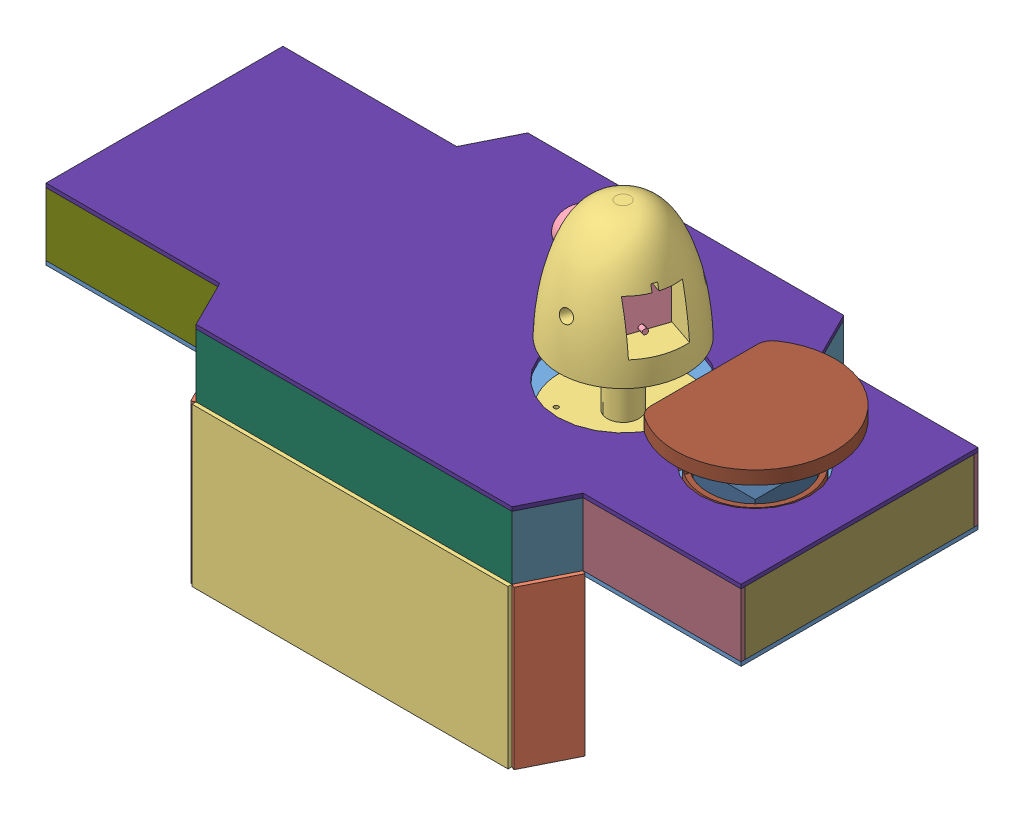
SolidWorks assembly ShellAssem, configuration Default. Lengths in mm.
Overall size (558.8 306.04 273.05).
46 component instances, 26 part files, 68 mates.
Components (placement in the parent):
- BasePlate-1: BasePlate [Default] at (-0.2928 -5.4567 3.8617) size (558.8 3.17 266.7)
- LowerPanelThin-1: LowerPanelThin [Default] at (-130.4678 -67.3692 118.1617) x (0.447214 0 0.894427) z (-0.894427 0 0.447214) size (42.6 127 3.17)
- LowerPanelThin-2: LowerPanelThin [Default] at (145.422 -67.3692 119.5816) x (-0.447214 0 0.894427) z (-0.894427 0 -0.447214) size (42.6 127 3.17)
- LowerPanelThin-3: LowerPanelThin [Default] at (-133.3076 -67.3692 -111.8582) x (-0.447214 0 0.894427) z (0.894427 0 0.447214) size (42.6 127 3.17)
- LowerPanelThin-4: LowerPanelThin [Default] at (142.5822 -67.3692 -110.4383) x (-0.447214 0 -0.894427) z (0.894427 0 -0.447214) size (42.6 127 3.17)
- LowerPanelWide-1: LowerPanelWide [Default] at (6.0572 -67.3692 -131.0758) size (254 127 3.17)
- LowerPanelWide-2: LowerPanelWide [Default] at (6.0572 -67.3692 138.7992) size (254 127 3.17)
- BatteryCaseLAssem-1: BatteryCaseLAssem [Default] at (-70.9297 -9.0701 32.2651) x (-1 0 0) z (0 0 -1) size (142.88 26.04 63.5)
  - BatteryCaseShort-1: BatteryCaseShort [Default] at (-92.8619 -9.4041 55.3909) size (114.3 22.86 3.17)
  - BatteryCaseLong-1: BatteryCaseLong [Default] at (-80.1619 -9.4041 115.7159) size (139.7 22.86 3.17)
  - BatteryCaseEnd-1: BatteryCaseEnd [Default] at (-8.7244 -9.4041 95.0784) x (0 0 1) z (0 -1 0) size (44.45 3.17 22.86)
  - Part7^BatteryCaseLAssem-1: Part7^BatteryCaseLAssem [Default] at origin (virtual)
  - Part8^BatteryCaseLAssem-1: Part8^BatteryCaseLAssem [Default] at origin (virtual)
  - Part9-1: Part9 [Default] at (0 -22.4216 0) x (1 0 0) z (0 1 0) size (142.88 63.5 3.17)
- BatteryCaseRAssem-1: BatteryCaseRAssem [Default] at (-70.9297 -27.8782 -24.5418) x (-1 0 0) z (0 0 1) size (142.88 26.04 63.5)
  - BatteryCaseShort-1: BatteryCaseShort [Default] at (-92.8619 -9.4041 55.3909) size (114.3 22.86 3.17)
  - BatteryCaseLong-1: BatteryCaseLong [Default] at (-80.1619 -9.4041 115.7159) size (139.7 22.86 3.17)
  - BatteryCaseEnd-1: BatteryCaseEnd [Default] at (-8.7244 -9.4041 95.0784) x (0 0 1) z (0 -1 0) size (44.45 3.17 22.86)
  - Part7^BatteryCaseRAssem-1: Part7^BatteryCaseRAssem [Default] at origin (virtual)
  - Part8^BatteryCaseRAssem-1: Part8^BatteryCaseRAssem [Default] at origin (virtual)
  - Part9-1: Part9 [Default] at (0 3.6134 0) x (1 0 0) z (0 1 0) size (142.88 63.5 3.17)
- NUC-1: NUC [Default] at (-220.6234 -3.8692 -63.9843) size (111 48.26 114.81)
- LIDAR_case-1: LIDAR_case [Default] at (245.1871 5.6558 53.8053) x (0 0 -1) z (1 0 0) size (128.27 85.36 108.59)
  - LIDAR_base-1: LIDAR_base [Default] at origin size (88.9 11.68 88.9)
  - LIDAR-1: LIDAR [Default] at (19.45 3.0942 -69.45) size (50 70.6 50)
  - LIDAR_top-1: LIDAR_top [Default] at (44.45 2.794 -44.45) x (0 0 -1) z (1 0 0) size (105.42 82.56 128.27)
- UpperFront-1: UpperFront [Default] at (-278.1053 21.5308 3.8617) x (0 0 1) z (-1 0 0) size (184.15 50.8 3.17)
- UpperFront-2: UpperFront [Default] at (277.5197 21.5308 3.8617) x (0 0 1) z (-1 0 0) size (184.15 50.8 3.17)
- UpperFrontWall-1: UpperFrontWall [Default] at (215.6072 21.5308 -89.8008) size (127 50.8 3.17)
- UpperFrontWall-2: UpperFrontWall [Default] at (215.6072 21.5308 97.5242) size (127 50.8 3.17)
- UpperAngleWallSmall-1: UpperAngleWallSmall [Default] at (141.1791 21.5308 117.4182) x (0.447214 0 -0.894427) z (0.894427 0 0.447214) size (42.67 50.8 3.17)
- UpperAngleWallSmall-3: UpperAngleWallSmall [Default] at (141.1791 21.5308 -109.6949) x (0.447214 0 0.894427) z (-0.894427 0 0.447214) size (42.67 50.8 3.17)
- UpperAngleWallSmall-4: UpperAngleWallSmall [Default] at (-129.0646 21.5308 -109.6949) x (0.447214 0 -0.894427) z (0.894427 0 0.447214) size (42.67 50.8 3.17)
- UpperAngleWallSmall-5: UpperAngleWallSmall [Default] at (-129.0646 21.5308 117.4182) x (-0.447214 0 -0.894427) z (0.894427 0 -0.447214) size (42.67 50.8 3.17)
- UpperAngleWallLarge-1: UpperAngleWallLarge [Default] at (6.0572 21.5308 -127.9008) size (254 50.8 3.17)
- UpperAngleWallLarge-2: UpperAngleWallLarge [Default] at (6.0572 21.5308 135.6242) size (254 50.8 3.17)
- UpperRearWall-1: UpperRearWall [Default] at (-209.8428 21.5308 97.5242) size (139.7 50.8 3.17)
- UpperRearWall-2: UpperRearWall [Default] at (-209.8428 21.5308 -89.8008) size (139.7 50.8 3.17)
- CoverPlate-1: CoverPlate [Default] at (-0.2928 48.5183 3.8617) size (558.8 3.17 266.7)
- LidarLift-1: LidarLift [Default] at (200.7371 0.8933 9.3553) size (88.9 9.53 88.9)
- pan_mechanism-2: pan_mechanism [Default] at (89.0568 -3.8692 3.8617) x (-0.411635 0 0.911349) z (-0.911349 0 -0.411635) size (126.7 179.04 129.89)
  - bottom_pan - Copy-1: bottom_pan - Copy [Default] at origin size (107.09 5.96 107.09)
  - top_pan-1: top_pan [Default] at (0 20.6883 0) x (0.97893 0 -0.204197) z (0.204197 0 0.97893) size (107.09 5.96 107.09)
  - Assem1-2: Assem1 [Default] at (0.0312 26.6446 -0.0302) x (0.99519 0 -0.097967) z (0.097967 0 0.99519) size (102.46 152.4 113.08)
    - among_us-1: among_us [Default] x (0 0 -1) z (1 0 0) size (103.27 152.4 102.46)
    - camera-1: camera [Default] at (0 95.3 -23.4507) size (38.5 38.2 90.38)
Mates (geometry in assembly coordinates):
- Coincident1: coincident anti-aligned: plane of BasePlate-1 through (-139.9928 -3.8692 99.1117) normal (-0.894427 0 0.447214); plane of LowerPanelThin-1 through (-130.4678 -67.3692 118.1617) normal (0.894427 0 -0.447214)
- Coincident2: coincident aligned: line of BasePlate-1 through (-139.9928 -3.8692 99.1117) axis (0 -1 0); line of LowerPanelThin-1 through (-139.9928 -3.8692 99.1117) axis (0 -1 0)
- Coincident3: coincident aligned: plane of BasePlate-1 through (-0.2928 -3.8692 3.8617) normal (0 1 0); plane of LowerPanelThin-1 through (-142.8326 -3.8692 100.5316) normal (0 1 0)
- Coincident4: coincident anti-aligned: plane of BasePlate-1 through (133.0572 -3.8692 137.2117) normal (0.894427 0 0.447214); plane of LowerPanelThin-2 through (142.5822 -67.3692 118.1617) normal (-0.894427 0 -0.447214)
- Coincident5: coincident aligned: plane of BasePlate-1 through (-0.2928 -3.8692 3.8617) normal (0 1 0); plane of LowerPanelThin-2 through (152.1072 -3.8692 99.1117) normal (0 1 0)
- Coincident6: coincident aligned: line of BasePlate-1 through (152.1072 -3.8692 99.1117) axis (0 -1 0); line of LowerPanelThin-2 through (152.1072 -3.8692 99.1117) axis (0 -1 0)
- Coincident7: coincident anti-aligned: plane of BasePlate-1 through (-139.9928 -3.8692 -91.3883) normal (-0.894427 0 -0.447214); plane of LowerPanelThin-3 through (-130.4678 -67.3692 -110.4383) normal (0.894427 0 0.447214)
- Coincident8: coincident aligned: plane of BasePlate-1 through (-0.2928 -3.8692 3.8617) normal (0 1 0); plane of LowerPanelThin-3 through (-120.9428 -3.8692 -129.4883) normal (0 1 0)
- Coincident9: coincident aligned: line of BasePlate-1 through (-139.9928 -3.8692 -91.3883) axis (0 -1 0); line of LowerPanelThin-3 through (-139.9928 -3.8692 -91.3883) axis (0 -1 0)
- Coincident10: coincident anti-aligned: plane of BasePlate-1 through (133.0572 -3.8692 -129.4883) normal (0.894427 0 -0.447214); plane of LowerPanelThin-4 through (142.5822 -67.3692 -110.4383) normal (-0.894427 0 0.447214)
- Coincident11: coincident aligned: plane of BasePlate-1 through (-0.2928 -3.8692 3.8617) normal (0 1 0); plane of LowerPanelThin-4 through (154.947 -3.8692 -92.8082) normal (0 1 0)
- Coincident12: coincident aligned: line of BasePlate-1 through (152.1072 -3.8692 -91.3883) axis (0 -1 0); line of LowerPanelThin-4 through (152.1072 -3.8692 -91.3883) axis (0 -1 0)
- Coincident13: coincident anti-aligned: plane of BasePlate-1 through (-120.9428 -3.8692 -129.4883) normal (0 0 -1); plane of LowerPanelWide-1 through (6.0572 -67.3692 -129.4883) normal (0 0 1)
- Coincident14: coincident aligned: plane of BasePlate-1 through (-0.2928 -3.8692 3.8617) normal (0 1 0); plane of LowerPanelWide-1 through (-120.9428 -3.8692 -129.4883) normal (0 1 0)
- Coincident16: coincident anti-aligned: line of LowerPanelThin-3 through (-120.9428 -130.8692 -129.4883) axis (0 1 0); line of LowerPanelWide-1 through (-120.9428 -3.8692 -129.4883) axis (0 -1 0)
- Coincident17: coincident anti-aligned: plane of BasePlate-1 through (-120.9428 -3.8692 137.2117) normal (0 0 1); plane of LowerPanelWide-2 through (6.0572 -67.3692 137.2117) normal (0 0 -1)
- Coincident18: coincident aligned: plane of BasePlate-1 through (-0.2928 -3.8692 3.8617) normal (0 1 0); plane of LowerPanelWide-2 through (-120.9428 -3.8692 140.3867) normal (0 1 0)
- Coincident19: coincident anti-aligned: line of LowerPanelThin-1 through (-120.9428 -130.8692 137.2117) axis (0 1 0); line of LowerPanelWide-2 through (-120.9428 -3.8692 137.2117) axis (0 -1 0)
- Coincident21: coincident aligned: line of BasePlate-1 through (-63.7928 -7.0442 -85.0383) axis (1 0 0); line of BatteryCaseLAssem-1/BatteryCaseLong-1 through (-60.6178 -7.0442 -85.0383) axis (1 0 0)
- Coincident22: coincident anti-aligned: line of BasePlate-1 through (-63.7928 -7.0442 -21.5383) axis (0 0 -1); line of BatteryCaseLAssem-1/BatteryCaseEnd-1 through (-63.7928 -7.0442 -85.0383) axis (0 0 1)
- Coincident23: coincident anti-aligned: line of BasePlate-1 through (-63.7928 -7.0442 92.7617) axis (1 0 0); line of BatteryCaseRAssem-1/BatteryCaseLong-1 through (79.0822 -7.0442 92.7617) axis (-1 0 0)
- Coincident24: coincident aligned: line of BasePlate-1 through (-63.7928 -7.0442 29.2617) axis (0 0 1); line of BatteryCaseRAssem-1/BatteryCaseEnd-1 through (-63.7928 -7.0442 48.3117) axis (0 0 1)
- Coincident25: coincident anti-aligned: plane of BasePlate-1 through (-0.2928 -3.8692 3.8617) normal (0 1 0); plane of NUC-1 through (-220.6234 -3.8692 50.8237) normal (0 -1 0)
- Coincident31: coincident anti-aligned: line of BasePlate-1 through (-276.5178 -3.8692 95.9367) axis (0 0 -1); line of UpperFront-1 through (-276.5178 -3.8692 -88.2133) axis (0 0 1)
- Coincident32: coincident anti-aligned: line of BasePlate-1 through (-279.6928 -3.8692 99.1117) axis (0 0 -1); line of UpperFront-1 through (-279.6928 -3.8692 -88.2133) axis (0 0 1)
- Coincident33: coincident: point of assembly; point of BasePlate-1; point of UpperFront-1
- Coincident34: coincident aligned: line of BasePlate-1 through (275.9322 -3.8692 -88.2133) axis (0 0 1); line of UpperFront-2 through (275.9322 -3.8692 -88.2133) axis (0 0 1)
- Coincident35: coincident aligned: line of BasePlate-1 through (279.1072 -3.8692 -91.3883) axis (0 0 1); line of UpperFront-2 through (279.1072 -3.8692 -88.2133) axis (0 0 1)
- Coincident36: coincident: point of assembly; point of BasePlate-1; point of UpperFront-2
- Coincident37: coincident anti-aligned: plane of UpperFront-2 through (275.9322 -3.8692 -88.2133) normal (0 0 -1); plane of UpperFrontWall-1 through (215.6072 21.5308 -88.2133) normal (0 0 1)
- Coincident38: coincident anti-aligned: plane of BasePlate-1 through (-0.2928 -3.8692 3.8617) normal (0 1 0); plane of UpperFrontWall-1 through (152.1072 -3.8692 -88.2133) normal (0 -1 0)
- Coincident39: coincident aligned: plane of BasePlate-1 through (279.1072 -3.8692 -91.3883) normal (1 0 0); plane of UpperFrontWall-1 through (279.1072 -3.8692 -88.2133) normal (1 0 0)
- Coincident40: coincident anti-aligned: plane of BasePlate-1 through (-0.2928 -3.8692 3.8617) normal (0 1 0); plane of UpperFrontWall-2 through (152.1072 -3.8692 99.1117) normal (0 -1 0)
- Coincident41: coincident aligned: plane of BasePlate-1 through (279.1072 -3.8692 -91.3883) normal (1 0 0); plane of UpperFrontWall-2 through (279.1072 -3.8692 99.1117) normal (1 0 0)
- Coincident42: coincident aligned: plane of BasePlate-1 through (152.1072 -3.8692 99.1117) normal (0 0 1); plane of UpperFrontWall-2 through (215.6072 21.5308 99.1117) normal (0 0 1)
- Coincident43: coincident anti-aligned: plane of BasePlate-1 through (-0.2928 -3.8692 3.8617) normal (0 1 0); plane of UpperAngleWallSmall-1 through (133.0572 -3.8692 137.2117) normal (0 -1 0)
- Coincident44: coincident anti-aligned: line of BasePlate-1 through (152.1072 -3.8692 99.1117) axis (-0.447214 0 0.894427); line of UpperAngleWallSmall-1 through (133.0572 -3.8692 137.2117) axis (0.447214 0 -0.894427)
- Coincident45: coincident: point of assembly; point of BasePlate-1; point of UpperAngleWallSmall-1
- Coincident47: coincident anti-aligned: plane of BasePlate-1 through (-0.2928 -3.8692 3.8617) normal (0 1 0); plane of UpperAngleWallSmall-5 through (-118.103 -3.8692 135.7918) normal (0 -1 0)
- Coincident48: coincident aligned: line of BasePlate-1 through (-120.9428 -3.8692 137.2117) axis (-0.447214 0 -0.894427); line of UpperAngleWallSmall-5 through (-120.9428 -3.8692 137.2117) axis (-0.447214 0 -0.894427)
- Coincident49: coincident: point of assembly; point of BasePlate-1; point of UpperAngleWallSmall-5
- Coincident50: coincident anti-aligned: plane of BasePlate-1 through (-0.2928 -3.8692 3.8617) normal (0 1 0); plane of UpperAngleWallSmall-4 through (-137.1865 -3.8692 -89.9014) normal (0 -1 0)
- Coincident51: coincident aligned: line of BasePlate-1 through (-139.9928 -3.8692 -91.3883) axis (0.447214 0 -0.894427); line of UpperAngleWallSmall-4 through (-140.0263 -3.8692 -91.3213) axis (0.447214 0 -0.894427)
- Coincident52: coincident: point of BasePlate-1; point of UpperAngleWallSmall-4
- Coincident53: coincident anti-aligned: plane of BasePlate-1 through (-0.2928 -3.8692 3.8617) normal (0 1 0); plane of UpperAngleWallSmall-3 through (130.2174 -3.8692 -128.0684) normal (0 -1 0)
- Coincident54: coincident aligned: line of BasePlate-1 through (133.0572 -3.8692 -129.4883) axis (0.447214 0 0.894427); line of UpperAngleWallSmall-3 through (133.0572 -3.8692 -129.4883) axis (0.447214 0 0.894427)
- Coincident56: coincident: point of assembly; point of BasePlate-1; point of UpperAngleWallSmall-3
- Coincident57: coincident anti-aligned: plane of BasePlate-1 through (-0.2928 -3.8692 3.8617) normal (0 1 0); plane of UpperAngleWallLarge-1 through (-120.9428 -3.8692 -126.3133) normal (0 -1 0)
- Coincident58: coincident aligned: line of BasePlate-1 through (-120.9428 -3.8692 -129.4883) axis (1 0 0); line of UpperAngleWallLarge-1 through (-120.9428 -3.8692 -129.4883) axis (1 0 0)
- Coincident59: coincident anti-aligned: line of UpperAngleWallSmall-4 through (-120.9428 -3.8692 -129.4883) axis (0 1 0); line of UpperAngleWallLarge-1 through (-120.9428 46.9308 -129.4883) axis (0 -1 0)
- Coincident60: coincident anti-aligned: plane of BasePlate-1 through (-0.2928 -3.8692 3.8617) normal (0 1 0); plane of UpperAngleWallLarge-2 through (-120.9428 -3.8692 137.2117) normal (0 -1 0)
- Coincident61: coincident anti-aligned: line of BasePlate-1 through (133.0572 -3.8692 137.2117) axis (-1 0 0); line of UpperAngleWallLarge-2 through (-120.9428 -3.8692 137.2117) axis (1 0 0)
- Coincident62: coincident anti-aligned: line of UpperAngleWallSmall-1 through (133.0572 46.9308 137.2117) axis (0 -1 0); line of UpperAngleWallLarge-2 through (133.0572 -3.8692 137.2117) axis (0 1 0)
- Coincident63: coincident anti-aligned: plane of BasePlate-1 through (-0.2928 -3.8692 3.8617) normal (0 1 0); plane of UpperRearWall-1 through (-279.6928 -3.8692 99.1117) normal (0 -1 0)
- Coincident64: coincident anti-aligned: line of BasePlate-1 through (-139.9928 -3.8692 99.1117) axis (-1 0 0); line of UpperRearWall-1 through (-279.6928 -3.8692 99.1117) axis (1 0 0)
- Coincident65: coincident aligned: plane of UpperFront-1 through (-279.6928 21.5308 3.8617) normal (-1 0 0); plane of UpperRearWall-1 through (-279.6928 -3.8692 99.1117) normal (-1 0 0)
- Coincident66: coincident aligned: plane of UpperFront-1 through (-279.6928 21.5308 3.8617) normal (-1 0 0); plane of UpperRearWall-2 through (-279.6928 -3.8692 -88.2133) normal (-1 0 0)
- Coincident67: coincident anti-aligned: plane of BasePlate-1 through (-0.2928 -3.8692 3.8617) normal (0 1 0); plane of UpperRearWall-2 through (-279.6928 -3.8692 -88.2133) normal (0 -1 0)
- Coincident68: coincident aligned: plane of BasePlate-1 through (-279.6928 -3.8692 -91.3883) normal (0 0 -1); plane of UpperRearWall-2 through (-209.8428 21.5308 -91.3883) normal (0 0 -1)
- Coincident69: coincident anti-aligned: plane of UpperFrontWall-1 through (152.1072 46.9308 -88.2133) normal (0 1 0); plane of CoverPlate-1 through (-0.2928 46.9308 3.8617) normal (0 -1 0)
- Coincident70: coincident aligned: plane of UpperAngleWallSmall-3 through (142.599 21.5308 -110.4048) normal (0.894427 0 -0.447214); plane of CoverPlate-1 through (133.0572 50.1058 -129.4883) normal (0.894427 0 -0.447214)
- Coincident71: coincident aligned: plane of UpperAngleWallSmall-1 through (142.599 21.5308 118.1282) normal (0.894427 0 0.447214); plane of CoverPlate-1 through (133.0572 50.1058 137.2117) normal (0.894427 0 0.447214)
- Coincident74: coincident aligned: circle of LIDAR_case-1/LIDAR_base-1; circle of LidarLift-1
- Coincident76: coincident anti-aligned: plane of BasePlate-1 through (-0.2928 -3.8692 3.8617) normal (0 1 0); plane of pan_mechanism-2/bottom_pan - Copy-1 through (89.0568 -3.8692 3.8617) normal (0 -1 0)
- Concentric1: concentric anti-aligned: cylinder of BasePlate-1 through (136.622 -24.1892 3.2661) axis (0 1 0) radius 1.4986; cylinder of pan_mechanism-2/bottom_pan - Copy-1 through (136.622 2.0871 3.2661) axis (0 -1 0) radius 1.4986
- Concentric2: concentric anti-aligned: circle of BasePlate-1; cylinder of pan_mechanism-2/bottom_pan - Copy-1 through (41.4917 2.0871 4.4572) axis (0 -1 0) radius 1.4986
- Coincident77: coincident anti-aligned: plane of BasePlate-1 through (-0.2928 -3.8692 3.8617) normal (0 1 0); plane of LidarLift-1 through (200.7371 -3.8692 9.3553) normal (0 -1 0)
- Parallel1: parallel anti-aligned: plane of LIDAR_case-1/LIDAR-1 through (225.7371 8.75 34.3553) normal (1 0 0); plane of UpperFront-2 through (275.9322 21.5308 3.8617) normal (-1 0 0)
